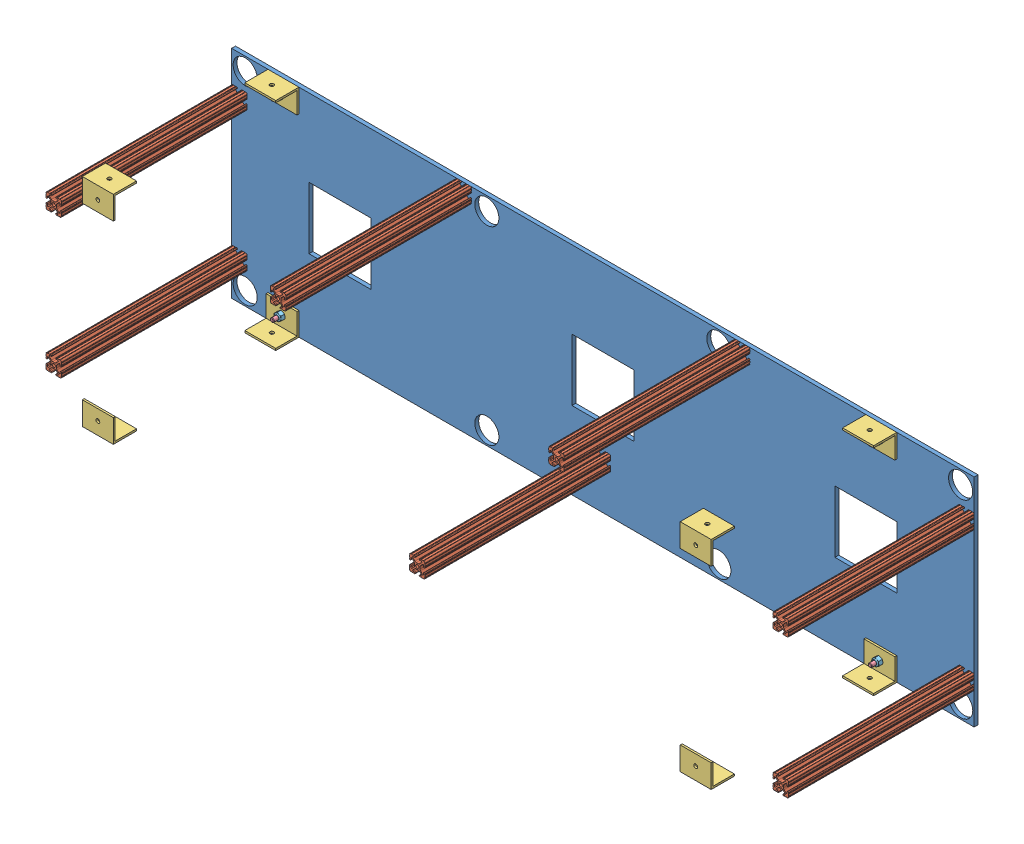
SolidWorks assembly GE-18046, configuration Default. Lengths in mm.
Overall size (1219.2 355.6 311.36).
31 component instances, 5 part files, 70 mates.
Components (placement in the parent):
- GE-18046-1: GE-18046 [Default] at (-621.5646 2.3189 -1203.4061) size (1219.2 355.6 6.35)
- GE-18030-1: GE-18030 [Default] at (-381 309.2498 158.75) size (25.4 25.4 304.8)
- GE-18030-2: GE-18030 [Default] at (-838.2 309.2498 158.75) x (-1 0 0) z (0 0 1) size (25.4 25.4 304.8)
- GE-18030-3: GE-18030 [Default] at (-12.7 258.4498 158.75) size (25.4 25.4 304.8)
- GE-18030-4: GE-18030 [Default] at (-609.6 42.5498 158.75) size (25.4 25.4 304.8)
- GE-18030-5: GE-18030 [Default] at (-1206.5 258.4498 158.75) x (0 1 0) z (0 0 1) size (25.4 25.4 304.8)
- GE-18030-6: GE-18030 [Default] at (-12.7 29.8498 158.75) size (25.4 25.4 304.8)
- GE-18030-7: GE-18030 [Default] at (-1206.5 29.8498 158.75) size (25.4 25.4 304.8)
- GE-18048-2: GE-18048 [Default] at (-1658.5487 321.9498 0) x (-1 0 0) z (0 0 1) size (50.8 38.1 38.1)
- GE-18048-3: GE-18048 [Default] at (-676.8744 321.9498 0) x (-1 0 0) z (0 0 1) size (50.8 38.1 38.1)
- GE-18048-4: GE-18048 [Default] at (372.0744 -33.6502 0) size (50.8 38.1 38.1)
- GE-18048-5: GE-18048 [Default] at (-609.6 321.9498 317.5) x (1 0 0) z (0 0 -1) size (50.8 38.1 38.1)
- GE-18048-6: GE-18048 [Default] at (372.0744 321.9498 317.5) x (1 0 0) z (0 0 -1) size (50.8 38.1 38.1)
- GE-18048-7: GE-18048 [Default] at (-1658.5487 -33.6502 317.5) x (-1 0 0) z (0 0 -1) size (50.8 38.1 38.1)
- GE-18048-8: GE-18048 [Default] at (-676.8744 -33.6502 317.5) x (-1 0 0) z (0 0 -1) size (50.8 38.1 38.1)
- GE-18048-1: GE-18048 [Default] at (-609.6 -33.6502 0) size (50.8 38.1 38.1)
- flat_hex_.25_20_1-19: flat_hex_.25_20_1 [91253A542] at (-12.7 29.8498 0) x (-0.999968 0.00803 0) z (0 0 -1) size (13.49 13.49 25.61)
- flat_hex_.25_20_1-20: flat_hex_.25_20_1 [91253A542] at (-152.4 -13.0127 0) x (-0.999968 0.00803 0) z (0 0 -1) size (13.49 13.49 25.61)
- flat_hex_.25_20_1-21: flat_hex_.25_20_1 [91253A542] at (-609.6 42.5498 0) x (-0.208353 0.978054 0) z (0 0 -1) size (13.49 13.49 25.61)
- flat_hex_.25_20_1-7: flat_hex_.25_20_1 [91253A542] at (-838.2 309.2498 0) x (-0.999968 0.00803 0) z (0 0 -1) size (13.49 13.49 25.61)
- flat_hex_.25_20_1-10: flat_hex_.25_20_1 [91253A542] at (-1134.0744 301.3123 0) x (-0.999968 0.00803 0) z (0 0 -1) size (13.49 13.49 25.61)
- flat_hex_.25_20_1-9: flat_hex_.25_20_1 [91253A542] at (-1206.5 258.4498 0) x (-0.999968 0.00803 0) z (0 0 -1) size (13.49 13.49 25.61)
- flat_hex_.25_20_1-15: flat_hex_.25_20_1 [91253A542] at (-1206.5 29.8498 0) x (-0.999968 0.00803 0) z (0 0 -1) size (13.49 13.49 25.61)
- flat_hex_.25_20_1-16: flat_hex_.25_20_1 [91253A542] at (-1134.0744 -13.0127 0) x (-0.233498 0.972357 0) z (0 0 -1) size (13.49 13.49 25.61)
- flat_hex_.25_20_1-17: flat_hex_.25_20_1 [91253A542] at (-381 309.2498 0) x (0.999968 -0.00803 0) z (0 0 -1) size (13.49 13.49 25.61)
- flat_hex_.25_20_1-18: flat_hex_.25_20_1 [91253A542] at (-152.4 301.3123 0) x (-0.988778 -0.149392 0) z (0 0 -1) size (13.49 13.49 25.61)
- flat_hex_.25_20_1-14: flat_hex_.25_20_1 [91253A542] at (-12.7 258.4498 0) x (-0.999968 0.00803 0) z (0 0 -1) size (13.49 13.49 25.61)
- nylock_.25_20-5: nylock_.25_20 [Default] at (-1134.0744 -13.0127 9.525) x (-0.594624 0.804004 0) z (0.804004 0.594624 0) size (11.11 7.94 12.83)
- nylock_.25_20-6: nylock_.25_20 [Default] at (-152.4 -13.0127 9.525) x (-0.594624 0.804004 0) z (0.804004 0.594624 0) size (11.11 7.94 12.83)
- nylock_.25_20-3: nylock_.25_20 [Default] at (-1134.0744 301.3123 9.525) x (0.932725 0.360589 0) z (0.360589 -0.932725 0) size (11.11 7.94 12.83)
- nylock_.25_20-4: nylock_.25_20 [Default] at (-152.4 301.3123 9.525) x (-0.594624 0.804004 0) z (0.804004 0.594624 0) size (11.11 7.94 12.83)
Mates (geometry in assembly coordinates):
- Parallel1: parallel aligned: plane of GE-18046-1 through (-1219.2 254.1025 6.35) normal (-1 0 0); plane of GE-18030-7 through (-1219.2 23.5167 311.15) normal (-1 0 0)
- Coincident3: coincident anti-aligned: plane of GE-18046-1 through (-609.6 144.1498 6.35) normal (0 0 1); plane of GE-18030-7 through (-1212.9164 20.4399 6.35) normal (0 0 -1)
- Concentric6: concentric anti-aligned: circle of GE-18046-1; cylinder of GE-18030-7 through (-1206.5 29.8498 311.15) axis (0 0 1) radius 2.6035
- Coincident5: coincident anti-aligned: plane of GE-18046-1 through (-609.6 144.1498 6.35) normal (0 0 1); plane of GE-18048-1 through (-609.6 144.1498 6.35) normal (0 0 -1)
- Concentric7: concentric aligned: circle of GE-18046-1; circle of GE-18048-1
- Concentric8: concentric anti-aligned: circle of GE-18046-1; circle of GE-18030-5
- Coincident6: coincident anti-aligned: plane of GE-18046-1 through (-609.6 144.1498 6.35) normal (0 0 1); plane of GE-18030-5 through (-1197.0902 252.0334 6.35) normal (0 0 -1)
- Concentric9: concentric aligned: circle of GE-18046-1; circle of GE-18048-2
- Coincident7: coincident anti-aligned: plane of GE-18046-1 through (-609.6 144.1498 6.35) normal (0 0 1); plane of GE-18048-2 through (-1658.5487 144.1498 6.35) normal (0 0 -1)
- Parallel2: parallel: line of GE-18046-1 through (1219.2 -1219.2 321.9498) axis (0 1 0); plane of GE-18048-2 through (-2223.6987 321.9498 9.525) normal (0 1 0)
- Concentric10: concentric anti-aligned: circle of GE-18046-1; circle of GE-18030-2
- Coincident9: coincident anti-aligned: plane of GE-18046-1 through (-609.6 144.1498 6.35) normal (0 0 1); plane of GE-18030-2 through (-831.7836 318.6596 6.35) normal (0 0 -1)
- Concentric11: concentric anti-aligned: circle of GE-18046-1; circle of GE-18030-1
- Coincident10: coincident anti-aligned: plane of GE-18046-1 through (-609.6 144.1498 6.35) normal (0 0 1); plane of GE-18030-1 through (-387.4164 299.8399 6.35) normal (0 0 -1)
- Concentric12: concentric aligned: circle of GE-18046-1; circle of GE-18048-3
- Coincident12: coincident anti-aligned: plane of GE-18046-1 through (-609.6 144.1498 6.35) normal (0 0 1); plane of GE-18048-3 through (-676.8744 144.1498 6.35) normal (0 0 -1)
- Concentric13: concentric anti-aligned: circle of GE-18046-1; circle of GE-18030-3
- Coincident13: coincident anti-aligned: plane of GE-18046-1 through (-609.6 144.1498 6.35) normal (0 0 1); plane of GE-18030-3 through (-19.1164 249.0399 6.35) normal (0 0 -1)
- Concentric14: concentric anti-aligned: circle of GE-18046-1; circle of GE-18030-6
- Coincident14: coincident anti-aligned: plane of GE-18046-1 through (-609.6 144.1498 6.35) normal (0 0 1); plane of GE-18030-6 through (-19.1164 20.4399 6.35) normal (0 0 -1)
- Concentric15: concentric anti-aligned: cylinder of GE-18046-1 through (-152.4 -13.0127 1310.1009) axis (0 0 1) radius 3.3782; circle of GE-18048-4
- Coincident15: coincident anti-aligned: plane of GE-18046-1 through (-609.6 144.1498 6.35) normal (0 0 1); plane of GE-18048-4 through (372.0744 144.1498 6.35) normal (0 0 -1)
- Concentric16: concentric anti-aligned: circle of GE-18046-1; cylinder of GE-18030-4 through (-609.6 42.5498 311.15) axis (0 0 1) radius 2.6035
- Coincident16: coincident anti-aligned: plane of GE-18046-1 through (-609.6 144.1498 6.35) normal (0 0 1); plane of GE-18030-4 through (-616.0164 33.1399 6.35) normal (0 0 -1)
- Coincident20: coincident aligned: line of GE-18048-7 through (-1108.6744 -33.6502 273.05) axis (0 0 1); line of GE-18048-1 through (-1108.6744 -33.6502 6.35) axis (0 0 1)
- Coincident22: coincident aligned: line of GE-18048-2 through (-1108.6744 321.9498 44.45) axis (0 0 -1); line of GE-18048-5 through (-1108.6744 321.9498 311.15) axis (0 0 -1)
- Coincident25: coincident aligned: line of GE-18048-3 through (-127 321.9498 44.45) axis (0 0 -1); line of GE-18048-6 through (-127 321.9498 311.15) axis (0 0 -1)
- Coincident27: coincident: line of GE-18048-4 through (-127 -33.6502 6.35) axis (0 0 1); plane of GE-18048-8 through (-127 -13.8364 307.975) normal (1 0 0)
- Coincident28: coincident aligned: plane of GE-18030-7 through (-1212.9164 20.4399 311.15) normal (0 0 1); plane of GE-18048-7 through (-1658.5487 144.1498 311.15) normal (0 0 1)
- Coincident30: coincident aligned: plane of GE-18030-5 through (-1197.0902 252.0334 311.15) normal (0 0 1); plane of GE-18048-5 through (-609.6 144.1498 311.15) normal (0 0 1)
- Coincident31: coincident aligned: plane of GE-18030-3 through (-19.1164 249.0399 311.15) normal (0 0 1); plane of GE-18048-6 through (372.0744 144.1498 311.15) normal (0 0 1)
- Coincident32: coincident aligned: plane of GE-18030-6 through (-19.1164 20.4399 311.15) normal (0 0 1); plane of GE-18048-8 through (-676.8744 144.1498 311.15) normal (0 0 1)
- Parallel5: parallel: plane of GE-18046-1 through (-44.45 -33.6502 6.35) normal (0 -1 0); line of GE-18030-4 through (-622.2998 31.9834 311.15) axis (0 0 -1)
- Parallel6: parallel: line of GE-18046-1 through (-1219.2 -33.6502 6.35) axis (1 0 0); plane of GE-18030-4 through (-619.1504 29.8498 311.15) normal (0 -1 0)
- Coincident37: coincident aligned: plane of GE-18046-1 through (-44.45 -33.6502 6.35) normal (0 -1 0); plane of GE-18048-1 through (-44.45 -33.6502 9.525) normal (0 -1 0)
- Coincident38: coincident aligned: plane of GE-18046-1 through (0 321.9498 6.35) normal (0 1 0); plane of GE-18048-3 through (-1242.0244 321.9498 9.525) normal (0 1 0)
- Coincident39: coincident aligned: plane of GE-18046-1 through (-44.45 -33.6502 6.35) normal (0 -1 0); plane of GE-18048-4 through (937.2244 -33.6502 9.525) normal (0 -1 0)
- Coincident41: coincident aligned: plane of GE-18048-4 through (937.2244 -33.6502 9.525) normal (0 -1 0); plane of GE-18048-8 through (-1242.0244 -33.6502 307.975) normal (0 -1 0)
- Coincident42: coincident aligned: plane of GE-18048-3 through (-1242.0244 321.9498 9.525) normal (0 1 0); plane of GE-18048-6 through (937.2244 321.9498 307.975) normal (0 1 0)
- Coincident43: coincident aligned: plane of GE-18048-2 through (-2223.6987 321.9498 9.525) normal (0 1 0); plane of GE-18048-5 through (-44.45 321.9498 307.975) normal (0 1 0)
- Coincident44: coincident aligned: plane of GE-18048-7 through (-2223.6987 -33.6502 307.975) normal (0 -1 0); plane of GE-18048-1 through (-44.45 -33.6502 9.525) normal (0 -1 0)
- Coincident45: coincident aligned: plane of GE-18046-1 through (-1219.2 254.1025 6.35) normal (-1 0 0); plane of GE-18030-5 through (-1219.2 252.1166 311.15) normal (-1 0 0)
- Coincident46: coincident aligned: plane of GE-18046-1 through (0 321.9498 6.35) normal (0 1 0); plane of GE-18030-2 through (-828.6496 321.9498 311.15) normal (0 1 0)
- Coincident47: coincident aligned: plane of GE-18046-1 through (0 321.9498 6.35) normal (0 1 0); plane of GE-18030-1 through (-371.4496 321.9498 311.15) normal (0 1 0)
- Coincident48: coincident aligned: plane of GE-18046-1 through (0 141.0032 6.35) normal (1 0 0); plane of GE-18030-3 through (0 264.7829 311.15) normal (1 0 0)
- Coincident49: coincident aligned: plane of GE-18046-1 through (0 141.0032 6.35) normal (1 0 0); plane of GE-18030-6 through (0 36.1829 311.15) normal (1 0 0)
- Coincident50: coincident anti-aligned: plane of GE-18046-1 through (-609.6 144.1498 0) normal (0 0 -1); plane of assembly through (0 0 0) normal (0 0 1)
- Coincident51: coincident aligned: plane of GE-18046-1 through (0 141.0032 6.35) normal (1 0 0); plane of assembly through (0 0 0) normal (1 0 0)
- Concentric17: concentric anti-aligned: circle of GE-18046-1; line of flat_hex_.25_20_1-19 through (-12.7 29.8498 25.4) axis (0 0 -1)
- Coincident53: coincident aligned: plane of GE-18046-1 through (-609.6 144.1498 0) normal (0 0 -1); plane of flat_hex_.25_20_1-19 through (-12.7255 26.6749 0) normal (0 0 -1)
- Concentric20: concentric anti-aligned: circle of GE-18046-1; line of flat_hex_.25_20_1-21 through (-609.6 42.5498 25.4) axis (0 0 -1)
- Coincident54: coincident aligned: plane of GE-18046-1 through (-609.6 144.1498 0) normal (0 0 -1); plane of flat_hex_.25_20_1-21 through (-612.7053 41.8883 0) normal (0 0 -1)
- Coincident56: coincident aligned: plane of GE-18046-1 through (-609.6 144.1498 0) normal (0 0 -1); circle of flat_hex_.25_20_1-7
- Concentric22: concentric anti-aligned: circle of GE-18046-1; line of flat_hex_.25_20_1-7 through (-838.2 309.2498 25.4) axis (0 0 -1)
- Coincident57: coincident aligned: plane of GE-18046-1 through (-609.6 144.1498 0) normal (0 0 -1); plane of flat_hex_.25_20_1-10 through (-1134.0999 298.1374 0) normal (0 0 -1)
- Concentric23: concentric anti-aligned: circle of GE-18046-1; line of flat_hex_.25_20_1-10 through (-1134.0744 301.3123 25.4) axis (0 0 -1)
- Coincident59: coincident aligned: plane of GE-18046-1 through (-609.6 144.1498 0) normal (0 0 -1); plane of flat_hex_.25_20_1-9 through (-1206.5255 255.2749 0) normal (0 0 -1)
- Concentric24: concentric anti-aligned: circle of GE-18046-1; line of flat_hex_.25_20_1-9 through (-1206.5 258.4498 25.4) axis (0 0 -1)
- Concentric25: concentric anti-aligned: circle of GE-18046-1; line of flat_hex_.25_20_1-15 through (-1206.5 29.8498 25.4) axis (0 0 -1)
- Coincident60: coincident aligned: plane of GE-18046-1 through (-609.6 144.1498 0) normal (0 0 -1); plane of flat_hex_.25_20_1-15 through (-1206.5255 26.6749 0) normal (0 0 -1)
- Coincident61: coincident aligned: plane of GE-18046-1 through (-609.6 144.1498 0) normal (0 0 -1); circle of flat_hex_.25_20_1-16
- Concentric26: concentric anti-aligned: circle of GE-18046-1; line of flat_hex_.25_20_1-16 through (-1134.0744 -13.0127 25.4) axis (0 0 -1)
- Coincident62: coincident aligned: plane of GE-18046-1 through (-609.6 144.1498 0) normal (0 0 -1); plane of flat_hex_.25_20_1-20 through (-152.4255 -16.1876 0) normal (0 0 -1)
- Concentric27: concentric anti-aligned: circle of GE-18046-1; line of flat_hex_.25_20_1-20 through (-152.4 -13.0127 25.4) axis (0 0 -1)
- Coincident63: coincident aligned: plane of GE-18046-1 through (-609.6 144.1498 0) normal (0 0 -1); plane of flat_hex_.25_20_1-17 through (-380.9745 312.4247 0) normal (0 0 -1)
- Concentric28: concentric anti-aligned: circle of GE-18030-1; line of flat_hex_.25_20_1-17 through (-381 309.2498 25.4) axis (0 0 -1)
- Concentric29: concentric aligned: circle of GE-18048-3; line of flat_hex_.25_20_1-18 through (-152.4 301.3123 25.4) axis (0 0 -1)
- Coincident64: coincident aligned: plane of GE-18046-1 through (-609.6 144.1498 0) normal (0 0 -1); plane of flat_hex_.25_20_1-18 through (-151.9257 298.1729 0) normal (0 0 -1)
- Coincident65: coincident aligned: plane of GE-18046-1 through (-609.6 144.1498 0) normal (0 0 -1); plane of flat_hex_.25_20_1-14 through (-12.7255 255.2749 0) normal (0 0 -1)
- Concentric30: concentric anti-aligned: circle of GE-18046-1; line of flat_hex_.25_20_1-14 through (-12.7 258.4498 25.4) axis (0 0 -1)
